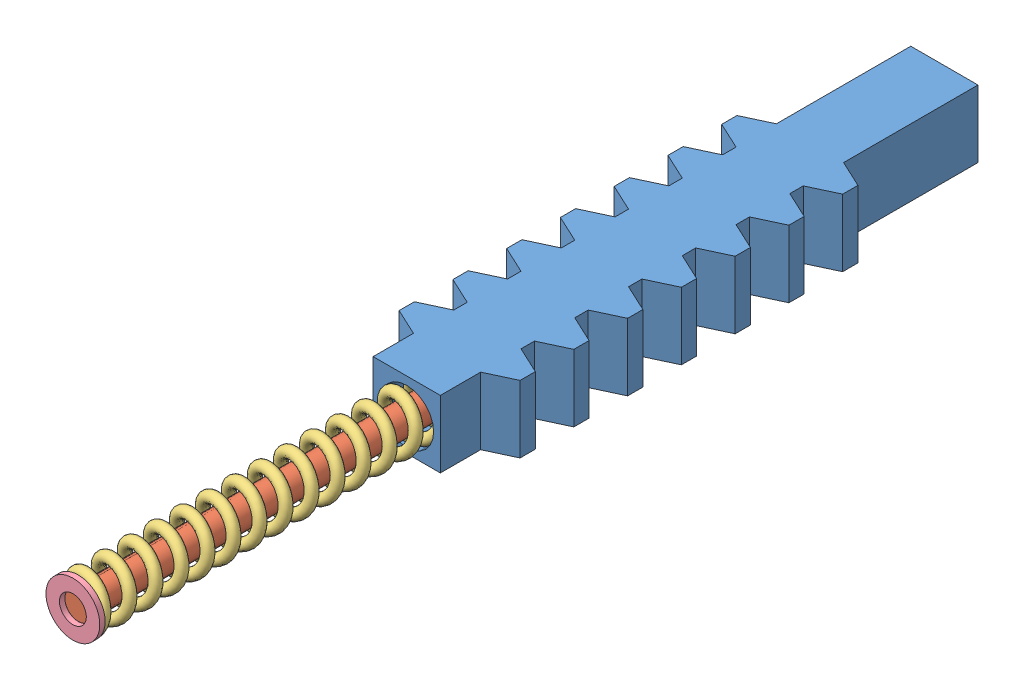
SolidWorks assembly Pinion assembly with spring, configuration Default. Lengths in mm.
Overall size (9 6.09 65.24).
4 component instances, 4 part files, 4 mates.
Components (placement in the parent):
- pinion gear-1: pinion gear [Default] at (18.4826 32.0454 18.0009) x (0 0 1) z (0 -1 0) size (40 9 5)
- Rod-1: Rod [Default] at (20.9826 29.4437 42.4391) x (-0.885268 -0.465081 0) z (0 0 1) size (2 2 60)
- spring-1: spring [Default] at (20.9826 29.4437 61.9854) x (-0.695169 0.718847 0) z (0.718847 0.695169 0) size (4 30.64 4.62)
- base-1: base [Default] at (20.9826 29.4437 102.4391) x (-0.953699 0.300764 0) z (0 0 1) size (4 4 0.4)
Mates (geometry in assembly coordinates):
- Concentric1: concentric aligned: cylinder of pinion gear-1 through (20.9826 29.4437 78.0009) axis (0 0 -1) radius 1; cylinder of Rod-1 through (20.9826 29.4437 102.4391) axis (0 0 -1) radius 1
- Tangent2: tangent: cylinder of pinion gear-1 through (20.9826 29.4437 73.0009) axis (0 0 1) radius 2; face of spring-1
- Tangent3: tangent: plane of pinion gear-1 through (20.9826 29.4437 73.0009) normal (0 0 1); circle of spring-1
- Coincident1: coincident aligned: circle of Rod-1; circle of base-1
